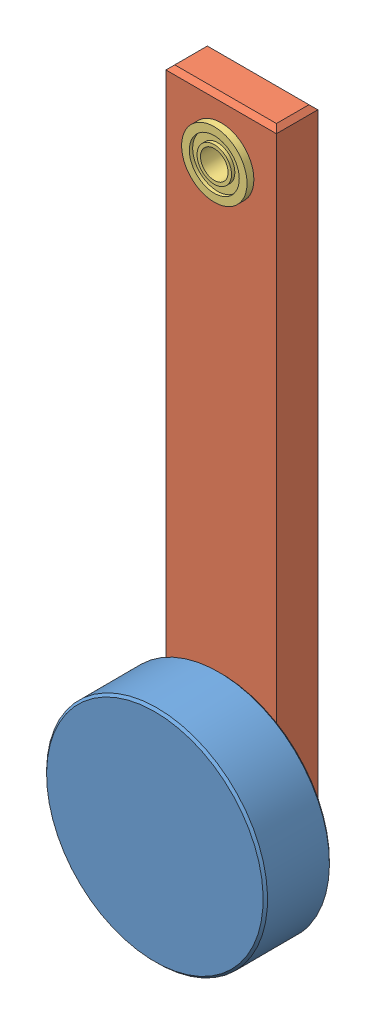
SolidWorks assembly bottom_link_assy, configuration Default. Lengths in mm.
Overall size (35.67 87.69 13.17).
5 component instances, 4 part files, 13 mates.
Components (placement in the parent):
- Mass_blank-1: Mass_blank [Default] at (0 -69.85 12.3825) x (0.784952 -0.619557 0) z (0 0 -1) size (25.4 25.4 7.62)
- bottom_link-1: bottom_link [Default] at (0 -6.35 4.7625) x (0 1 0) z (-1 0 0) size (76.2 4.76 12.7)
- FR144-ZZ-1: FR144-ZZ [Default] at (0 -6.35 2.7464) size (7.52 7.52 2.8)
- FR144-ZZ-2: FR144-ZZ [Default] at (0 -6.35 2.0161) x (-0.923728 -0.383049 0) z (0 0 -1) size (7.52 7.52 2.8)
- 92805A108_Stainless Steel Thread-Locking Hex Drive Flat Head Screws-1: 92805A108_Stainless Steel Thread-Locking Hex Drive Flat Head Screws [92805A108] at (0 -69.85 4.8324) x (-0.88408 -0.467336 0) z (0 0 -1) size (6.48 6.48 9.8)
Mates (geometry in assembly coordinates):
- Concentric31: concentric aligned: cylinder of Mass_blank-1 through (0 -69.85 4.7625) axis (0 0 -1) radius 1.1303; cylinder of bottom_link-1 through (0 -69.85 0) axis (0 0 -1) radius 1.632
- Coincident41: coincident anti-aligned: plane of bottom_link-1 through (0 -6.35 4.7625) normal (0 0 1); plane of Mass_blank-1 through (0 -69.85 4.7625) normal (0 0 -1)
- Coincident42: coincident anti-aligned: plane of bottom_link-1 through (0 -6.35 0) normal (0 0 -1); plane of ? through (1.8032 -65.5164 0) normal (0 0 1)
- Concentric32: concentric: cylinder of bottom_link-1 through (0 -63.5 0) axis (0 0 -1) radius 1.632; cylinder of ? through (0 -63.5 -1.4986) axis (0 0 -1) radius 2.7051
- Symmetric1: symmetric aligned: plane of bottom_link-1 through (-6.35 -6.35 0) normal (-1 0 0); plane of bottom_link-1 through (6.35 -6.35 0) normal (1 0 0); plane of assembly through (0 0 0) normal (1 0 0)
- Coincident43: coincident anti-aligned: plane of bottom_link-1 through (0 -6.35 0) normal (0 0 -1); plane of assembly through (0 0 0) normal (0 0 1)
- Coincident44: coincident aligned: plane of bottom_link-1 through (0 0 0) normal (0 1 0); plane of assembly through (0 0 0) normal (0 1 0)
- Coincident46: coincident aligned: plane of bottom_link-1 through (0 -6.35 0) normal (0 0 -1); circle of FR144-ZZ-2
- Concentric34: concentric anti-aligned: cylinder of bottom_link-1 through (0 -6.35 4.7625) axis (0 0 -1) radius 3.1623; cylinder of FR144-ZZ-2 through (0 -6.35 0) axis (0 0 1) radius 3.175
- Coincident47: coincident anti-aligned: plane of bottom_link-1 through (0 -6.35 4.7625) normal (0 0 1); plane of FR144-ZZ-1 through (0 -6.35 4.7625) normal (0 0 -1)
- Concentric35: concentric aligned: cylinder of bottom_link-1 through (0 -6.35 4.7625) axis (0 0 -1) radius 3.1623; cylinder of FR144-ZZ-1 through (0 -6.35 4.7625) axis (0 0 -1) radius 3.175
- Concentric36: concentric aligned: cylinder of bottom_link-1 through (0 -69.85 0) axis (0 0 -1) radius 1.632; cylinder of 92805A108_Stainless Steel Thread-Locking Hex Drive Flat Head Screws-1 through (0 -69.85 0.0699) axis (0 0 -1) radius 3.2385
- Coincident48: coincident aligned: cone of bottom_link-1 through (0 -69.85 0) axis (0 0 1); cone of 92805A108_Stainless Steel Thread-Locking Hex Drive Flat Head Screws-1 through (0 -69.85 2.2645) axis (0 0 1)
